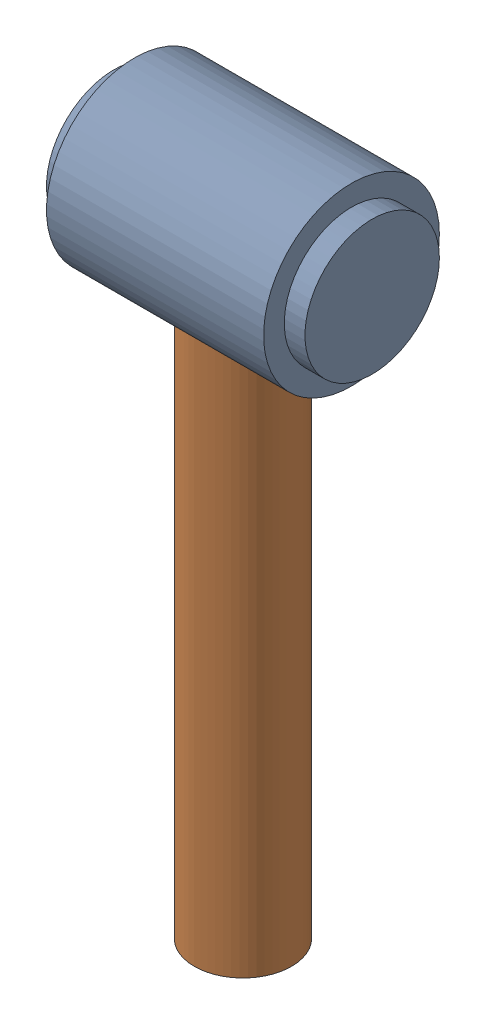
SolidWorks assembly Ensemble axe de fixation, configuration Défaut. Lengths in mm.
Overall size (25 68.5 17).
2 component instances, 2 part files, 1 mates.
Components (placement in the parent):
- Pivot de fixation-1: Pivot de fixation [Défaut] at (5.8751 17.8586 0) size (25 17 17)
- axe de fixation-1: axe de fixation [Défaut] at (-6.6249 -42.1414 0) x (0.468613 0 0.883404) z (0 1 0) size (9.4 9.4 60)
Mates (geometry in assembly coordinates):
- Coïncidente2: coincident: circle of Pivot de fixation-1 centre (-6.6249 17.8586 0) axis (0 1 0); circle of axe de fixation-1 centre (-6.6249 17.8586 0) axis (0 1 0)
